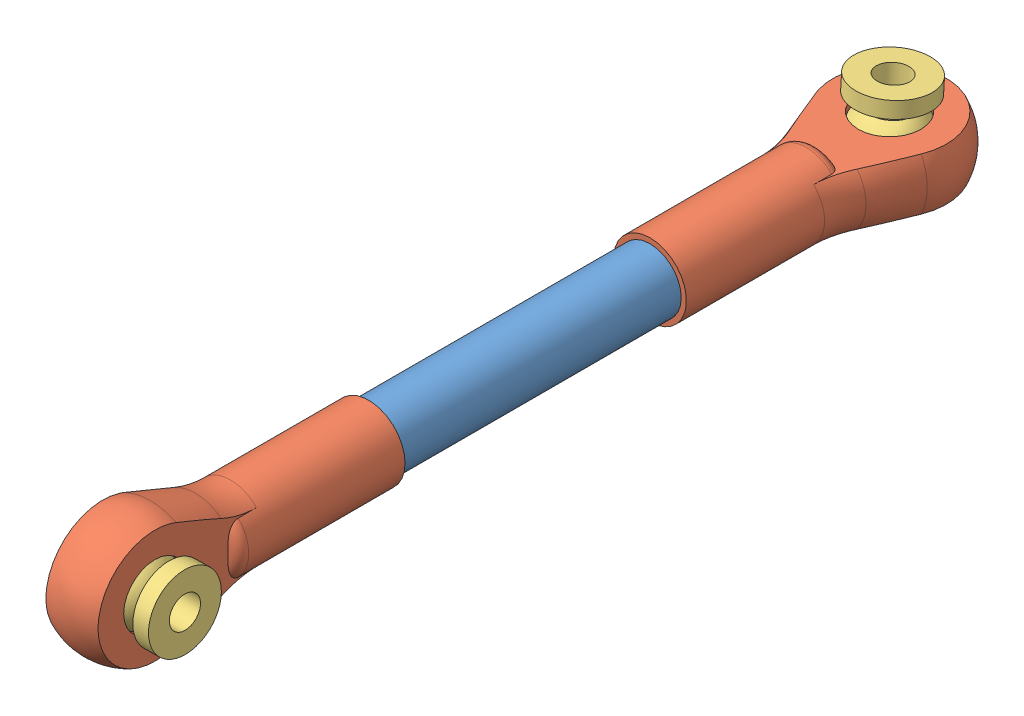
SolidWorks assembly Bar_1, configuration Default. Lengths in mm.
Overall size (12 12 85).
5 component instances, 3 part files, 8 mates.
Components (placement in the parent):
- Bar_1-1: Bar_1 [Default] at origin size (6 6 55)
- Ball_socket-1: Ball_socket [Default] at (0 0 56) x (-1 0 0) z (0 0 -1) size (7 12 29)
- Ball_socket-2: Ball_socket [Default] at (0 0 -1) x (0 1 0) z (0 0 1) size (7 12 29)
- Ball_2-1: Ball_2 [Default] at (0.0697 -3.6154 -8.7091) x (0.21417 -0.074228 -0.973972) z (0.019212 -0.996595 0.080177) size (7 7 9)
- Ball_2-2: Ball_2 [Default] at (-3.6275 -0.0422 64.0021) x (0.006187 -0.487895 0.872881) z (-0.999932 -0.011625 0.000591) size (7 7 9)
Mates (geometry in assembly coordinates):
- Concentric1: concentric aligned: cylinder of Bar_1-1 through (0 0 55) axis (0 0 -1) radius 3; cylinder of Ball_socket-2 through (0 0 14) axis (0 0 -1) radius 3
- Concentric2: concentric anti-aligned: cylinder of Bar_1-1 through (0 0 55) axis (0 0 -1) radius 3; cylinder of Ball_socket-1 through (0 0 41) axis (0 0 1) radius 3
- Perpendicular1: perpendicular: plane of Ball_socket-1 through (2.5 -17.5 56) normal (1 0 0); plane of Ball_socket-2 through (17.5 -2.5 -1) normal (0 -1 0)
- Coincident2: coincident anti-aligned: plane of Bar_1-1 through (0 0 0) normal (0 0 -1); plane of Ball_socket-2 through (0 0 0) normal (0 0 1)
- Coincident3: coincident anti-aligned: plane of Bar_1-1 through (0 0 55) normal (0 0 1); plane of Ball_socket-1 through (0 0 55) normal (0 0 -1)
- Parallel1: parallel aligned: plane of Ball_socket-2 through (17.5 2.5 -1) normal (0 1 0); plane of assembly through (0 0 0) normal (0 1 0)
- Concentric3: concentric: sphere of Ball_socket-2; sphere of Ball_2-1
- Concentric4: concentric: sphere of Ball_socket-1; sphere of Ball_2-2
